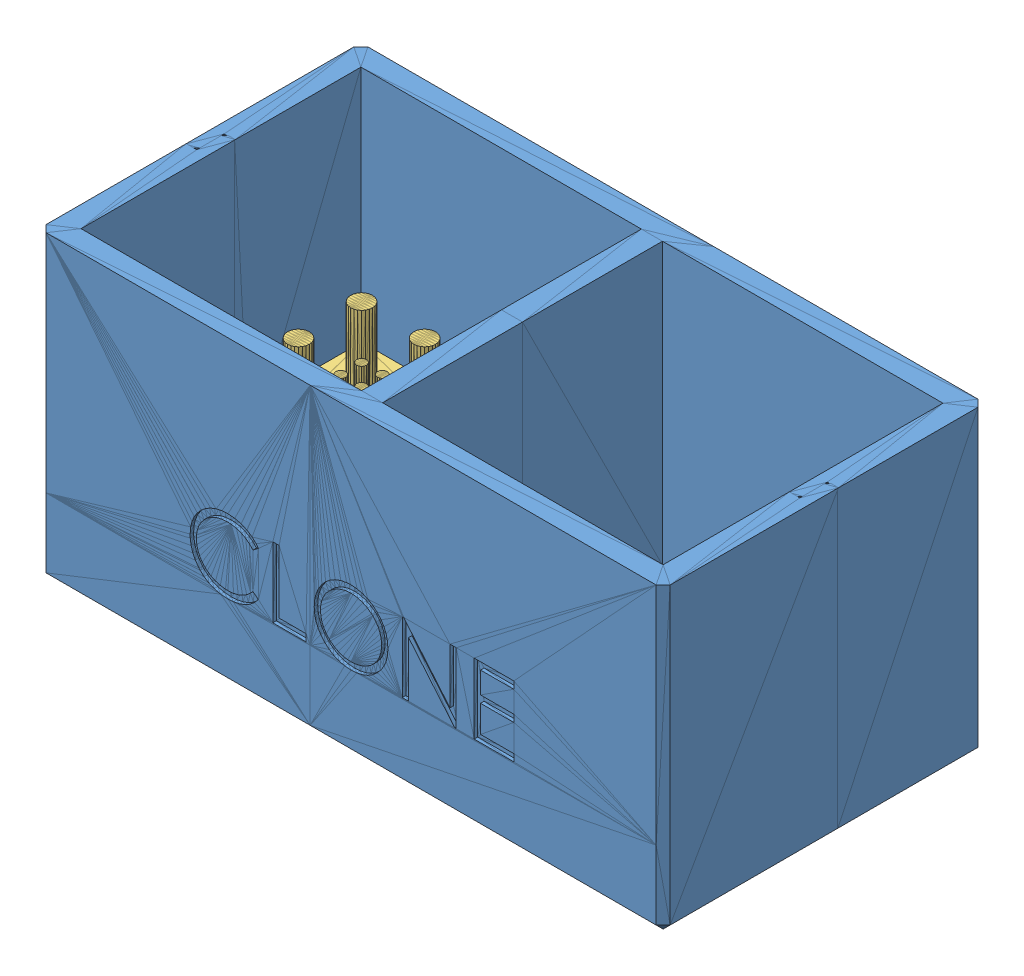
SolidWorks assembly Assem1, configuration Default. Lengths in mm.
Overall size (89 43 45.9).
4 component instances, 3 part files, 8 mates.
Components (placement in the parent):
- ZButt_1U_Clone_NoHassle-1: ZButt_1U_Clone_NoHassle [Default] at (-87.5237 15.5725 -13.475) size (89 43 26.95)
- ZButt_1U_Clone_NoHassle-2: ZButt_1U_Clone_NoHassle [Default] at (1.4763 15.5725 32.425) x (-1 0 0) z (0 0 -1) size (89 43 26.95)
- ZButt_1U_CloneRiser_Cavity-1: ZButt_1U_CloneRiser_Cavity [Default] at (-64.5237 18.5725 9.425) x (1 0 0) z (0 1 0) size (40 40 8)
- ZButt_1U_StemCavity-1: ZButt_1U_StemCavity [Default] at (-64.5237 28.5725 9.425) x (0 0 -1) z (0 1 0) size (32 32 19)
Mates (geometry in assembly coordinates):
- Coincident1: coincident aligned: plane of ZButt_1U_Clone_NoHassle-1 through (-87.5237 15.5725 -13.475) normal (-1 0 0); plane of ZButt_1U_Clone_NoHassle-2 through (-87.5237 15.5725 32.425) normal (-1 0 0)
- Coincident2: coincident aligned: plane of ZButt_1U_Clone_NoHassle-1 through (-87.5237 15.5725 -13.475) normal (0 -1 0); plane of ZButt_1U_Clone_NoHassle-2 through (1.4763 15.5725 32.425) normal (0 -1 0)
- Coincident3: coincident anti-aligned: plane of ZButt_1U_Clone_NoHassle-1 through (-87.5237 15.5725 13.475) normal (0 0 1); plane of ZButt_1U_Clone_NoHassle-2 through (1.4763 15.5725 13.475) normal (0 0 -1)
- Coincident4: coincident anti-aligned: plane of ZButt_1U_Clone_NoHassle-2 through (1.4763 18.5725 32.425) normal (0 1 0); plane of ZButt_1U_CloneRiser_Cavity-1 through (-64.5237 18.5725 9.425) normal (0 -1 0)
- Coincident5: coincident: plane of ZButt_1U_Clone_NoHassle-2 through (1.4763 15.5725 29.425) normal (0 0 -1); line of ZButt_1U_CloneRiser_Cavity-1 through (-44.5237 19.5725 29.425) axis (-1 0 0)
- Coincident6: coincident: plane of ZButt_1U_Clone_NoHassle-2 through (-44.5237 15.5725 32.425) normal (-1 0 0); line of ZButt_1U_CloneRiser_Cavity-1 through (-44.5237 19.5725 29.425) axis (0 0 -1)
- Coincident9: coincident: line of ZButt_1U_CloneRiser_Cavity-1 through (-80.5237 26.5725 -6.575) axis (1 0 0); line of ZButt_1U_StemCavity-1 through (-97.825 26.5725 -6.575) axis (1 0 0)
- Coincident10: coincident aligned: line of ZButt_1U_CloneRiser_Cavity-1 through (-80.5237 26.5725 25.425) axis (0 0 -1); line of ZButt_1U_StemCavity-1 through (-80.5237 26.5725 25.425) axis (0 0 -1)
